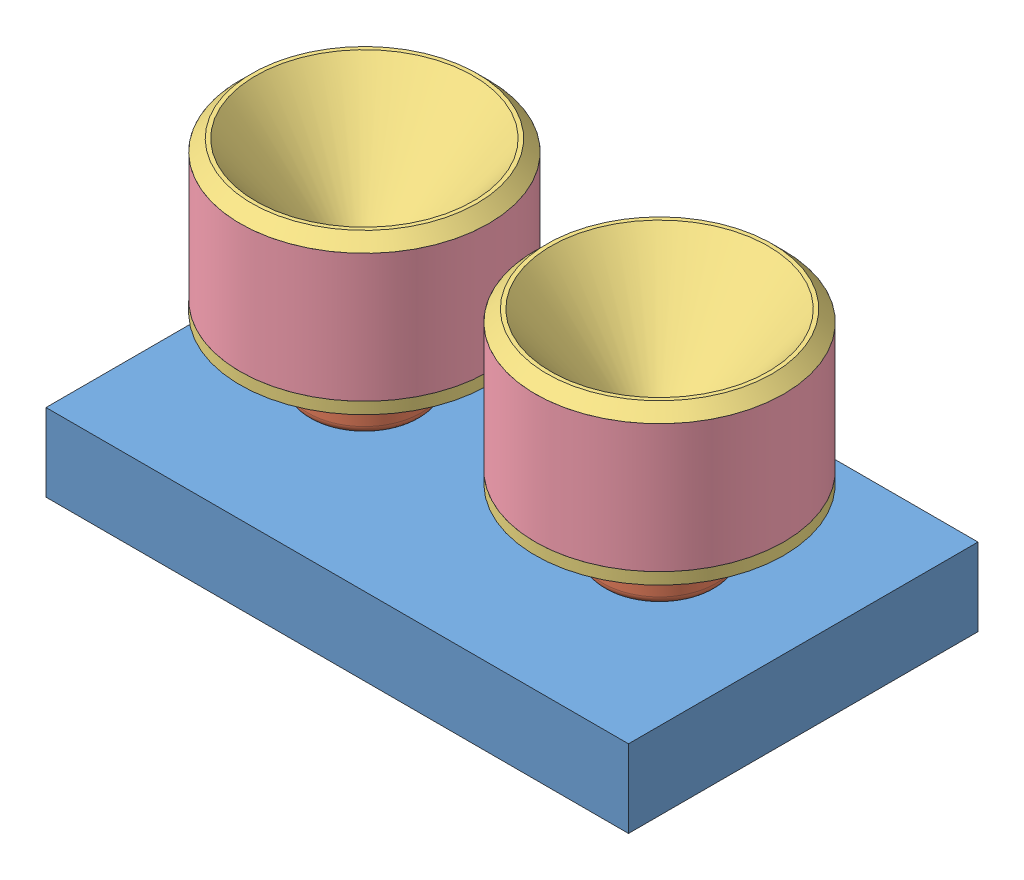
SolidWorks assembly MS-A-0016-Flywheel Assembly, configuration Default. Lengths in mm.
Overall size (150 76 90).
9 component instances, 5 part files, 16 mates.
Components (placement in the parent):
- MS-P-0053- 22xx Flywheel Base-1: MS-P-0053- 22xx Flywheel Base [Default] at (75.0209 62.1497 116.0535) size (150 20 90)
- MS-P-0057-2204 2300 Motor -1: MS-P-0057-2204 2300 Motor  [Default] at (37.0209 82.1497 116.0535) x (-0.999243 0 0.038902) z (-0.038902 0 -0.999243) size (29 32 29)
- MS-P-0057-2204 2300 Motor -2: MS-P-0057-2204 2300 Motor  [Default] at (113.0209 82.1497 116.0535) x (0.978619 0 -0.205681) z (0.205681 0 0.978619) size (29 32 29)
- MS-P-0055- Flywheel-1: MS-P-0055- Flywheel [Default] at (37.0209 99.1497 116.0535) x (0.995456 0 0.095226) z (-0.095226 0 0.995456) size (64 39 64)
- MS-P-0055- Flywheel-2: MS-P-0055- Flywheel [Default] at (113.0209 99.1497 116.0535) x (0.99958 0 -0.028991) z (0.028991 0 0.99958) size (64 39 64)
- MS-P-0056- Flywheel Rubber-1: MS-P-0056- Flywheel Rubber [Default] at (37.0209 102.1497 116.0535) size (64 33 64)
- MS-P-0056- Flywheel Rubber-2: MS-P-0056- Flywheel Rubber [Default] at (113.0209 102.1497 116.0535) size (64 33 64)
- MS-P-0054- M5 Lock Nut-1: MS-P-0054- M5 Lock Nut [90576A104] at (37.0209 107.1497 116.0535) x (0.999974 0 0.007147) z (-0.007147 0 0.999974) size (8 5.15 9.24)
- MS-P-0054- M5 Lock Nut-2: MS-P-0054- M5 Lock Nut [90576A104] at (113.0209 107.1497 116.0535) x (-0.860881 0 -0.508806) z (0.508806 0 -0.860881) size (8 5.15 9.24)
Mates (geometry in assembly coordinates):
- Concentric1: concentric anti-aligned: circle of Motor Base-1; circle of 2204 2203 motor-1
- Coincident2: coincident anti-aligned: plane of Motor Base-1 through (75.0209 82.1497 116.0535) normal (0 1 0); plane of 2204 2203 motor-1 through (37.0209 82.1497 116.0535) normal (0 -1 0)
- Concentric2: concentric anti-aligned: circle of Motor Base-1; circle of 2204 2203 motor-2
- Coincident5: coincident anti-aligned: plane of Motor Base-1 through (75.0209 82.1497 116.0535) normal (0 1 0); plane of 2204 2203 motor-2 through (113.0209 82.1497 116.0535) normal (0 -1 0)
- Concentric6: concentric anti-aligned: circle of 2204 2203 motor-1; circle of Flywheel v3-1
- Coincident6: coincident anti-aligned: plane of 2204 2203 motor-1 through (37.0209 99.1497 116.0535) normal (0 1 0); plane of Flywheel v3-1 through (37.0209 99.1497 116.0535) normal (0 -1 0)
- Concentric7: concentric anti-aligned: circle of 2204 2203 motor-2; circle of Flywheel v3-2
- Coincident7: coincident anti-aligned: plane of 2204 2203 motor-2 through (113.0209 99.1497 116.0535) normal (0 1 0); plane of Flywheel v3-2 through (113.0209 99.1497 116.0535) normal (0 -1 0)
- Concentric8: concentric aligned: cylinder of Flywheel v3-1 through (37.0209 99.1497 116.0535) axis (0 -1 0) radius 28; cylinder of flywheel rubber-1 through (37.0209 135.1497 116.0535) axis (0 -1 0) radius 28
- Coincident8: coincident anti-aligned: plane of Flywheel v3-1 through (37.0209 102.1497 116.0535) normal (0 1 0); plane of flywheel rubber-1 through (37.0209 102.1497 116.0535) normal (0 -1 0)
- Concentric9: concentric aligned: cylinder of Flywheel v3-2 through (113.0209 99.1497 116.0535) axis (0 -1 0) radius 28; cylinder of flywheel rubber-2 through (113.0209 135.1497 116.0535) axis (0 -1 0) radius 28
- Coincident9: coincident anti-aligned: plane of Flywheel v3-2 through (113.0209 102.1497 116.0535) normal (0 1 0); plane of flywheel rubber-2 through (113.0209 102.1497 116.0535) normal (0 -1 0)
- Concentric10: concentric anti-aligned: circle of Flywheel v3-1; circle of m5 lock nut-1
- Coincident12: coincident anti-aligned: plane of Flywheel v3-1 through (37.0209 107.1497 116.0535) normal (0 1 0); plane of m5 lock nut-1 through (33.0705 107.1497 109.0969) normal (0 -1 0)
- Concentric11: concentric aligned: circle of Flywheel v3-2; circle of m5 lock nut-2
- Coincident15: coincident anti-aligned: plane of Flywheel v3-2 through (113.0209 107.1497 116.0535) normal (0 1 0); plane of m5 lock nut-2 through (112.9393 107.1497 124.0531) normal (0 -1 0)
